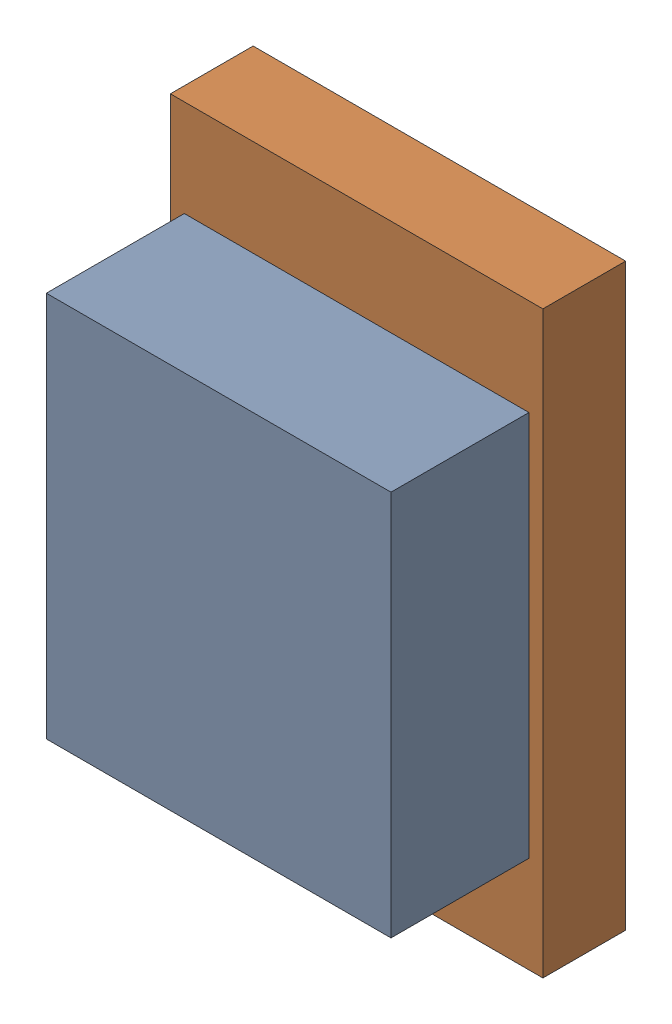
SolidWorks assembly D4, configuration Default. Lengths in mm.
Overall size (1.35 2.1 0.8).
4 component instances, 2 part files, 0 mates.
Components (placement in the parent):
- 6638399248-1: 6638399248 [Default] at (6.985 34.925 0.3) size (1.25 1.4 0.5)
  - Extruded_12-1: Extruded_12 [Default] at origin size (1.25 1.4 0.5)
- 6638399088-1: 6638399088 [Default] at (6.985 34.925 0) size (1.35 2.1 0.3)
  - Extruded_13-1: Extruded_13 [Default] at origin size (1.35 2.1 0.3)
